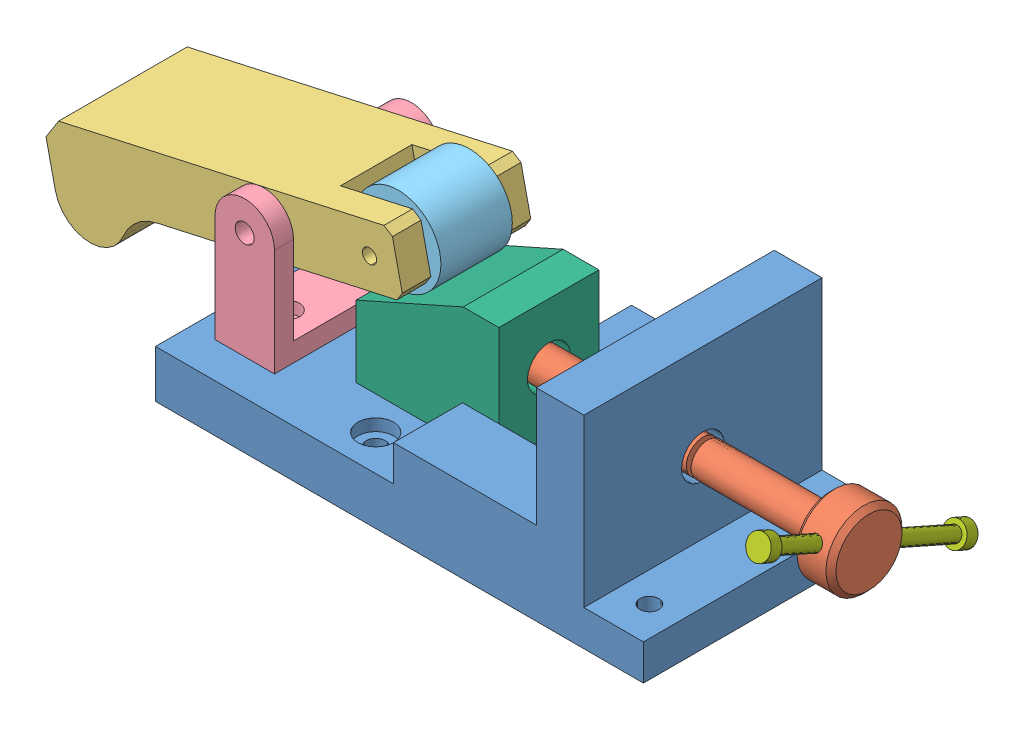
SolidWorks assembly Assem1_yT, configuration Default. Lengths in mm.
Overall size (320.26 92.87 100.66).
7 component instances, 7 part files, 17 mates.
Components (placement in the parent):
- Part1_prj_yT1-1: Part1_prj_yT1 [Default] at (265.7708 95.0553 112.6781) size (205 85 100)
- Part2_prj_yT1-1: Part2_prj_yT1 [Default] at (133.5401 113.6995 162.6781) x (1 0 0) z (0 0.404703 0.914448) size (151.35 32 32)
- Part3-1: Part3 [Default] at (-48.4039 114.3572 135.6781) x (0.976168 0.217015 0) z (0 0 1) size (150 40 54)
- Part4-1: Part4 [Default] at (-20.8379 88.6995 154.6322) x (0 0 1) z (-1 0 0) size (70 57.5 25)
- Part5-1: Part5 [Default] at (25.4168 143.5737 147.6781) size (36 36 30)
- Part6-1: Part6 [Default] at (52.0051 105.7583 141.6781) size (60 50 42)
- Part7-1: Part7 [Default] at (200.6113 117.2203 170.6335) x (0 -0.404703 -0.914448) z (0 0.914448 -0.404703) size (95 10 10)
Mates (geometry in assembly coordinates):
- Coincident1: coincident: plane of assembly; plane of assembly; plane of Part1_prj_yT1-1 through (-41.4989 88.6995 212.6781) normal (0 1 0); plane of Part4-1 through (-20.8379 88.6995 154.6322) normal (0 -1 0)
- Concentric1: concentric: circle of assembly; circle of assembly; circle of Part1_prj_yT1-1; circle of Part4-1
- Concentric2: concentric: circle of assembly; circle of assembly; circle of Part1_prj_yT1-1; circle of Part4-1
- Concentric7: concentric: cylinder of assembly; cylinder of assembly; cylinder of Part1_prj_yT1-1 through (112.5011 113.6995 162.6781) axis (1 0 0) radius 9; cylinder of Part2_prj_yT1-1 through (56.9011 113.6995 162.6781) axis (-1 0 0) radius 7
- Coincident3: coincident: circle of assembly; plane of assembly; circle of Part1_prj_yT1-1; plane of Part2_prj_yT1-1 through (118.5011 120.1006 159.8452) normal (-1 0 0)
- Coincident4: coincident: plane of assembly; plane of assembly; plane of Part3-1 through (-91.9392 104.6788 189.6781) normal (0 0 1); plane of Part4-1 through (-18.9989 133.6995 189.6781) normal (0 0 -1)
- Coincident5: coincident: circle of assembly; cylinder of assembly; circle of Part3-1; cylinder of Part4-1 through (-18.9989 133.6995 189.6781) axis (0 0 1) radius 4
- Lock1: lock: unknown of Part2_prj_yT1-1; unknown of Part7-1
- Parallel1: parallel: plane of assembly; plane of assembly; plane of Part2_prj_yT1-1 through (133.5401 113.6995 162.6781) normal (0 0.914448 -0.404703); plane of Part7-1 through (200.6113 117.2203 170.6335) normal (0 0.914448 -0.404703)
- Coincident6: coincident: plane of assembly; plane of assembly; plane of Part3-1 through (46.1369 105.6669 177.6781) normal (0 0 -1); plane of Part5-1 through (25.4168 143.5737 177.6781) normal (0 0 1)
- Coincident7: coincident: circle of assembly; circle of assembly; circle of Part3-1; circle of Part5-1
- Coincident8: coincident: plane of assembly; plane of assembly; plane of Part1_prj_yT1-1 through (58.5011 88.6995 183.6781) normal (0 0 -1); plane of Part6-1 through (52.0051 105.7583 183.6781) normal (0 0 1)
- Parallel2: parallel: cylinder of assembly; cylinder of assembly; cylinder of Part2_prj_yT1-1 through (56.9011 113.6995 162.6781) axis (-1 0 0) radius 7; cylinder of Part6-1 through (33.7698 113.6995 162.6781) axis (1 0 0) radius 9
- Tangent1: tangent: cylinder of assembly; plane of assembly; cylinder of Part5-1 through (25.4168 143.5737 177.6781) axis (0 0 -1) radius 18; plane of Part6-1 through (58.7698 138.6995 183.6781) normal (-0.406138 0.913812 0)
- Coincident10: coincident: plane of assembly; plane of assembly; plane of Part1_prj_yT1-1 through (-41.4989 88.6995 212.6781) normal (0 1 0); plane of Part6-1 through (13.7698 88.6995 183.6781) normal (0 -1 0)
- LimitDistance1: limit distance = 23.1314 mm: plane of assembly; plane of assembly; plane of Part6-1 through (33.7698 113.6995 162.6781) normal (1 0 0); plane of Part2_prj_yT1-1 through (56.9011 120.1006 159.8452) normal (-1 0 0)
- Screw1: screw = 4 mm: cylinder of assembly; cylinder of assembly; cylinder of Part2_prj_yT1-1 through (56.9011 113.6995 162.6781) axis (-1 0 0) radius 7; cylinder of Part6-1 through (33.7698 113.6995 162.6781) axis (1 0 0) radius 9
